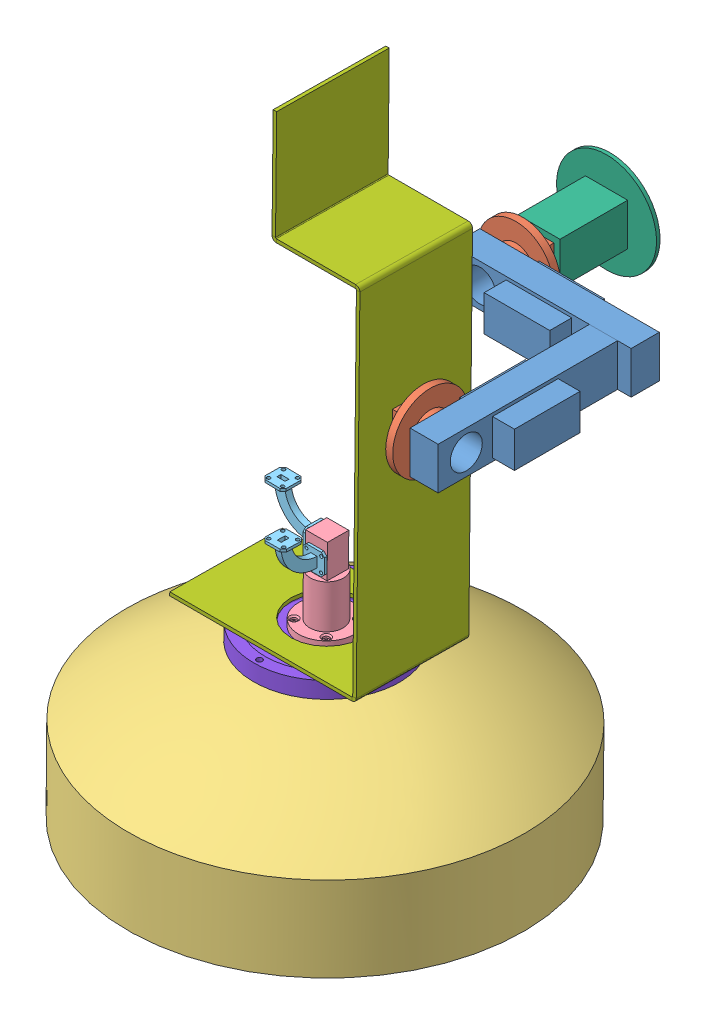
SolidWorks assembly DIsh, 12-Inch Pan and Tilt, Mobile hood node, configuration Default. Lengths in mm.
Overall size (403.62 578.06 562.45).
11 component instances, 8 part files, 26 mates.
Components (placement in the parent):
- Pan and tilt L-1: Pan and tilt L [Default] at origin size (161.93 38.1 49.48)
- Pan and tilt L-2: Pan and tilt L [Default] at (124.2822 0 187.325) x (0 0 -1) z (1 0 0) size (161.93 38.1 49.48)
- gear pan tilt-1: gear pan tilt [Default] at (25.4 0 -6.985) x (-0.003815 -0.999993 0) z (0 0 -1) size (67.95 67.95 27.86)
- gear pan tilt-2: gear pan tilt [Default] at (117.2972 0 161.925) x (0 0.010498 0.999945) z (-1 0 0) size (67.95 67.95 27.86)
- Dish, mobile hood node-1: Dish, mobile hood node [Default] at (25.4 -270.6221 164.766) x (0.989325 -0.00153 -0.145716) z (-0.145724 -0.010386 -0.989271) size (355.6 143.51 355.6)
- RF Outlet, Mobile hoodnode-1: RF Outlet, Mobile hoodnode [Default] at (25.4 -196.9661 163.9928) x (0 0.999945 -0.010498) z (1 0 0) size (74.83 50.04 50.04)
- WR 28 right angle hard way-1: WR 28 right angle hard way [Default] at (15.494 -131.6663 163.3073) x (0 0.999945 -0.010498) z (0 0.010498 0.999945) size (39.85 39.75 19.18)
- WR 28 right angle hard way-2: WR 28 right angle hard way [Default] at (25.4 -139.8196 173.0454) x (0 0.999945 -0.010498) z (1 0 0) size (39.85 39.75 19.18)
- pan and tilt base-1: pan and tilt base [Default] at (25.4 0 -88.9508) x (1 0 0) z (0 -1 0) size (90.17 64.26 90.17)
- Bracket, Dish pan-tilt-1: Bracket, Dish pan-tilt [Default] at (99.9998 -0.5333 111.1278) x (-1 0 0) z (0 0.999945 -0.010498) size (168.28 101.6 422.28)
- Mount, Dish, Disk-1: Mount, Dish, Disk [Default] at (25.4 -208.3955 164.1128) x (1 0 0) z (0 0.999945 -0.010498) size (130.81 130.81 15.88)
Mates (geometry in assembly coordinates):
- Coincident1: coincident anti-aligned: plane of Pan and tilt L-1 through (0 0 25.4) normal (0 0 1); plane of Pan and tilt L-2 through (149.6822 -19.05 25.4) normal (0 0 -1)
- Coincident2: coincident aligned: line of Pan and tilt L-1 through (124.2822 -19.05 25.4) axis (0 1 0); line of Pan and tilt L-2 through (124.2822 -19.05 25.4) axis (0 1 0)
- Coincident3: coincident aligned: line of Pan and tilt L-1 through (149.6822 -19.05 25.4) axis (-1 0 0); line of Pan and tilt L-2 through (149.6822 -19.05 25.4) axis (-1 0 0)
- Coincident4: coincident anti-aligned: plane of Pan and tilt L-2 through (124.2822 0 187.325) normal (-1 0 0); plane of gear pan tilt-2 through (124.2822 0 161.925) normal (1 0 0)
- Concentric1: concentric anti-aligned: cylinder of Pan and tilt L-2 through (119.9896 0 161.925) axis (1 0 0) radius 14.4653; cylinder of gear pan tilt-2 through (124.2822 0 161.925) axis (-1 0 0) radius 10.2616
- Coincident5: coincident anti-aligned: plane of Pan and tilt L-1 through (0 0 0) normal (0 0 -1); plane of gear pan tilt-1 through (25.4 0 0) normal (0 0 1)
- Concentric2: concentric anti-aligned: cylinder of Pan and tilt L-1 through (25.4 0 -4.2926) axis (0 0 1) radius 14.4653; cylinder of gear pan tilt-1 through (25.4 0 0) axis (0 0 -1) radius 10.2616
- Parallel1: parallel aligned: plane of Pan and tilt L-1 through (0 0 45.1866) normal (0 0 1); plane of RF Outlet, Mobile hoodnode-1
- Parallel2: parallel aligned: plane of Pan and tilt L-2 through (119.9896 0 187.325) normal (-1 0 0); plane of RF Outlet, Mobile hoodnode-1 through (15.494 -122.2432 153.5558) normal (-1 0 0)
- Coincident9: coincident anti-aligned: plane of RF Outlet, Mobile hoodnode-1 through (15.494 -122.2432 153.5558) normal (-1 0 0); plane of WR 28 right angle hard way-1 through (15.494 -131.6663 163.3073) normal (1 0 0)
- Concentric6: concentric aligned: cylinder of RF Outlet, Mobile hoodnode-1 through (20.574 -137.9453 170.1045) axis (-1 0 0) radius 1.4224; cylinder of WR 28 right angle hard way-1 through (15.494 -137.9453 170.1045) axis (-1 0 0) radius 1.4224
- Concentric7: concentric aligned: cylinder of RF Outlet, Mobile hoodnode-1 through (20.574 -125.246 169.9712) axis (-1 0 0) radius 1.4224; cylinder of WR 28 right angle hard way-1 through (15.494 -125.246 169.9712) axis (-1 0 0) radius 1.4224
- Coincident10: coincident anti-aligned: plane of RF Outlet, Mobile hoodnode-1 through (35.306 -122.0405 172.8587) normal (0 0.010498 0.999945); plane of WR 28 right angle hard way-2 through (25.4 -139.8196 173.0454) normal (0 -0.010498 -0.999945)
- Concentric8: concentric aligned: cylinder of RF Outlet, Mobile hoodnode-1 through (18.669 -146.2225 168.0323) axis (0 0.010498 0.999945) radius 1.4224; cylinder of WR 28 right angle hard way-2 through (18.669 -146.1692 173.112) axis (0 0.010498 0.999945) radius 1.4224
- Concentric9: concentric aligned: cylinder of RF Outlet, Mobile hoodnode-1 through (18.669 -133.5232 167.899) axis (0 0.010498 0.999945) radius 1.4224; cylinder of WR 28 right angle hard way-2 through (18.669 -133.4699 172.9787) axis (0 0.010498 0.999945) radius 1.4224
- Coincident12: coincident anti-aligned: plane of gear pan tilt-1 through (25.4 0 -27.8638) normal (0 0 -1); plane of pan and tilt base-1 through (25.4 0 -27.8638) normal (0 0 1)
- Concentric10: concentric anti-aligned: circle of gear pan tilt-1; cylinder of pan and tilt base-1 through (25.4 0 -92.1258) axis (0 0 1) radius 45.085
- Coincident13: coincident anti-aligned: plane of gear pan tilt-2 through (103.1748 0 161.925) normal (-1 0 0); plane of Bracket, Dish pan-tilt-1 through (103.1748 0.5333 212.7222) normal (1 0 0)
- Width1: width anti-aligned: plane of Bracket, Dish pan-tilt-1 through (99.2632 -193.1311 214.7553) normal (0 0.010498 0.999945); plane of Bracket, Dish pan-tilt-1 through (99.2632 129.6345 109.7613) normal (0 -0.010498 -0.999945); plane of gear pan tilt-2 through (103.1748 20.1056 141.3928) normal (0 -0.010498 -0.999945); plane of gear pan tilt-2 through (103.1748 20.5322 182.0306) normal (0 0.010498 0.999945)
- Concentric11: concentric anti-aligned: cylinder of RF Outlet, Mobile hoodnode-1 through (25.4 -190.9975 163.9301) axis (0 -0.999945 0.010498) radius 25.019; cylinder of Bracket, Dish pan-tilt-1 through (25.4 -193.6643 163.9581) axis (0 0.999945 -0.010498) radius 31.75
- Coincident16: coincident aligned: plane of gear pan tilt-2; plane of Bracket, Dish pan-tilt-1 through (99.9998 -0.5333 111.1278) normal (0 0.999945 -0.010498)
- Concentric12: concentric aligned: circle of Dish, mobile hood node-1; circle of Mount, Dish, Disk-1
- Coincident17: coincident aligned: circle of Dish, mobile hood node-1; plane of Mount, Dish, Disk-1 through (25.4 -203.3158 164.0594) normal (0 -0.999945 0.010498)
- Concentric13: concentric aligned: cylinder of RF Outlet, Mobile hoodnode-1 through (25.4 -190.9975 163.9301) axis (0 -0.999945 0.010498) radius 25.019; cylinder of Mount, Dish, Disk-1 through (25.4 -193.6643 163.9581) axis (0 -0.999945 0.010498) radius 4.826
- Coincident18: coincident anti-aligned: plane of RF Outlet, Mobile hoodnode-1 through (25.4 -196.9661 163.9928) normal (0 -0.999945 0.010498); plane of Mount, Dish, Disk-1 through (25.4 -196.9661 163.9928) normal (0 0.999945 -0.010498)
- Coincident19: coincident anti-aligned: plane of Bracket, Dish pan-tilt-1 through (99.9998 -193.1311 214.7553) normal (0 -0.999945 0.010498); plane of Mount, Dish, Disk-1 through (25.4 -193.6643 163.9581) normal (0 0.999945 -0.010498)
